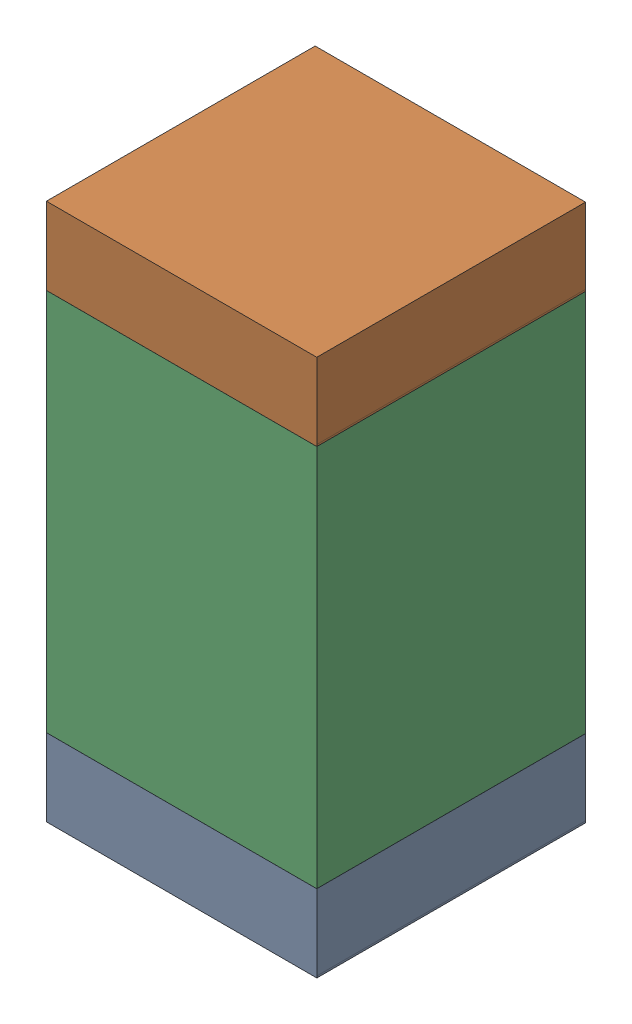
SolidWorks assembly C7, configuration ﾃﾞﾌｫﾙﾄ. Lengths in mm.
Overall size (0.81 1.6 0.8).
6 component instances, 2 part files, 0 mates.
Components (placement in the parent):
- 6641443168-1: 6641443168 [ﾃﾞﾌｫﾙﾄ] at (12.3314 3.3249 -2.6339) size (0.8 0.23 0.8)
  - Extruded-24-1: Extruded-24 [ﾃﾞﾌｫﾙﾄ] at origin size (0.8 0.23 0.8)
- 6641443168-2: 6641443168 [ﾃﾞﾌｫﾙﾄ] at (12.3314 4.6949 -2.6339) size (0.8 0.23 0.8)
  - Extruded-24-1: Extruded-24 [ﾃﾞﾌｫﾙﾄ] at origin size (0.8 0.23 0.8)
- 6641442768-1: 6641442768 [ﾃﾞﾌｫﾙﾄ] at (12.3313 4.0099 -2.6339) size (0.8 1.14 0.8)
  - Extruded-25-1: Extruded-25 [ﾃﾞﾌｫﾙﾄ] at origin size (0.8 1.14 0.8)
